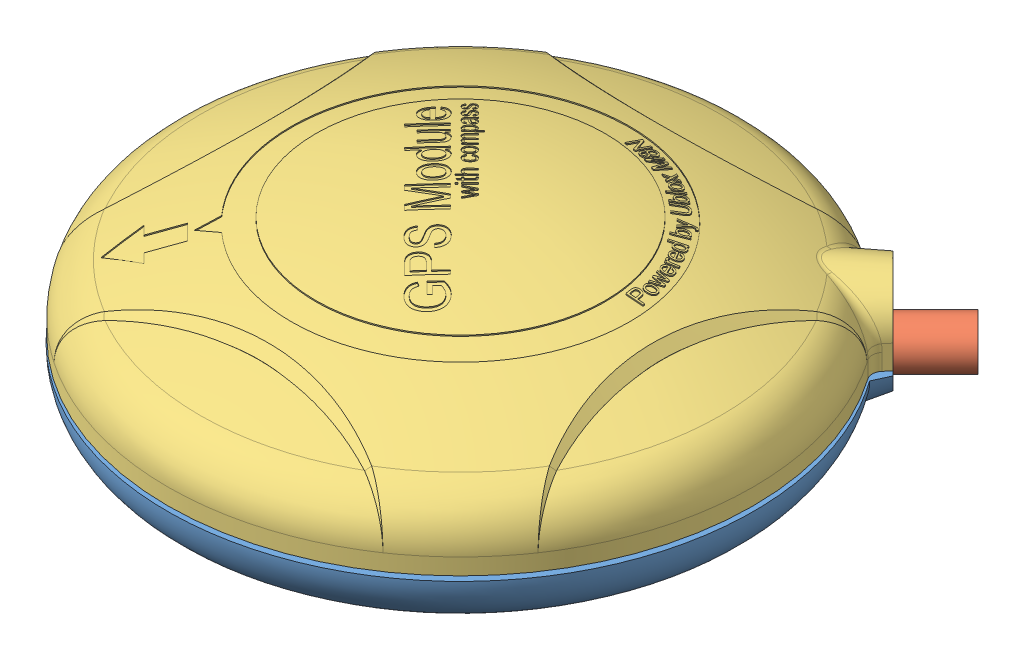
SolidWorks assembly GPS модуль Ublox NEO-M8N-0-01, configuration По умолчанию. Lengths in mm.
Overall size (76.65 16.3 76.65).
7 component instances, 4 part files, 8 mates.
Components (placement in the parent):
- Основание-1: Основание [По умолчанию] at (1.251 2.1668 -0.218) size (53.7 6.4 53.7)
- Модуль GPS Ublox NEO-M8N-0-01-1: Модуль GPS Ublox NEO-M8N-0-01 [По умолчанию] at (1.251 1.9668 -0.218) x (0 0 -1) z (1 0 0) size (40.83 9.84 40.83)
- Крышка-1: Крышка [По умолчанию] at (1.251 1.0668 -0.218) x (-0.707107 0 -0.707107) z (0.707107 0 -0.707107) size (53.6 11.16 54.8)
- pan head cross recess screw_din-12: pan head cross recess screw_din [DIN EN ISO 7045 - M1.6 x 5 - Z - 5N] at (18.751 -2.4332 -0.218) x (0 1 0) z (0 0 1) size (6.27 3.2 3.2)
- pan head cross recess screw_din-16: pan head cross recess screw_din [DIN EN ISO 7045 - M1.6 x 5 - Z - 5N] at (1.251 -2.4332 -17.718) x (0 1 0) z (1 0 0) size (6.27 3.2 3.2)
- pan head cross recess screw_din-17: pan head cross recess screw_din [DIN EN ISO 7045 - M1.6 x 5 - Z - 5N] at (-16.249 -2.4332 -0.218) x (0 1 0) z (0 0 -1) size (6.27 3.2 3.2)
- pan head cross recess screw_din-18: pan head cross recess screw_din [DIN EN ISO 7045 - M1.6 x 5 - Z - 5N] at (1.251 -2.4332 17.282) x (0 1 0) z (-1 0 0) size (6.27 3.2 3.2)
Mates (geometry in assembly coordinates):
- Совпадение1: coincident anti-aligned: plane of Модуль GPS Ublox NEO-M8N-0-01-1 through (1.251 3.1668 -0.218) normal (0 1 0); plane of Крышка-1 through (1.251 3.1668 -0.218) normal (0 -1 0)
- Расстояние1: distance = 0.35 mm anti-aligned: plane of Модуль GPS Ublox NEO-M8N-0-01-1 through (-14.399 3.1668 15.432) normal (0 0 1); plane of Крышка-1 through (17.251 500001.0668 15.782) normal (0 0 -1)
- Расстояние2: distance = 0.35 mm anti-aligned: plane of Модуль GPS Ublox NEO-M8N-0-01-1 through (-14.399 3.1668 15.432) normal (-1 0 0); plane of Крышка-1 through (-14.749 500001.0668 -16.218) normal (1 0 0)
- Концентричный1: concentric aligned: cylinder of Основание-1 through (1.251 2.1668 -0.218) axis (0 1 0) radius 25.9; cylinder of Крышка-1 through (1.251 12.0668 -0.218) axis (0 1 0) radius 26.8
- Совпадение5: coincident aligned: plane of Основание-1 through (21.05 2.1668 -20.017) normal (0.707107 0 -0.707107); plane of Крышка-1 through (21.05 1.0668 -20.017) normal (0.707107 0 -0.707107)
- Совпадение6: coincident anti-aligned: plane of Основание-1 through (1.251 1.9668 -0.218) normal (0 1 0); plane of Модуль GPS Ublox NEO-M8N-0-01-1 through (1.251 1.9668 -0.218) normal (0 -1 0)
- Концентричный6: concentric aligned: cylinder of Основание-1 through (18.751 -3.8332 -0.218) axis (0 -1 0) radius 0.95; cylinder of pan head cross recess screw_din-1 through (18.751 -27.8332 -0.218) axis (0 -1 0) radius 1.6
- Совпадение11: coincident anti-aligned: plane of Основание-1 through (19.701 -1.1332 -0.218) normal (0 -1 0); plane of pan head cross recess screw_din-1 through (17.951 -1.1332 -0.218) normal (0 1 0)
